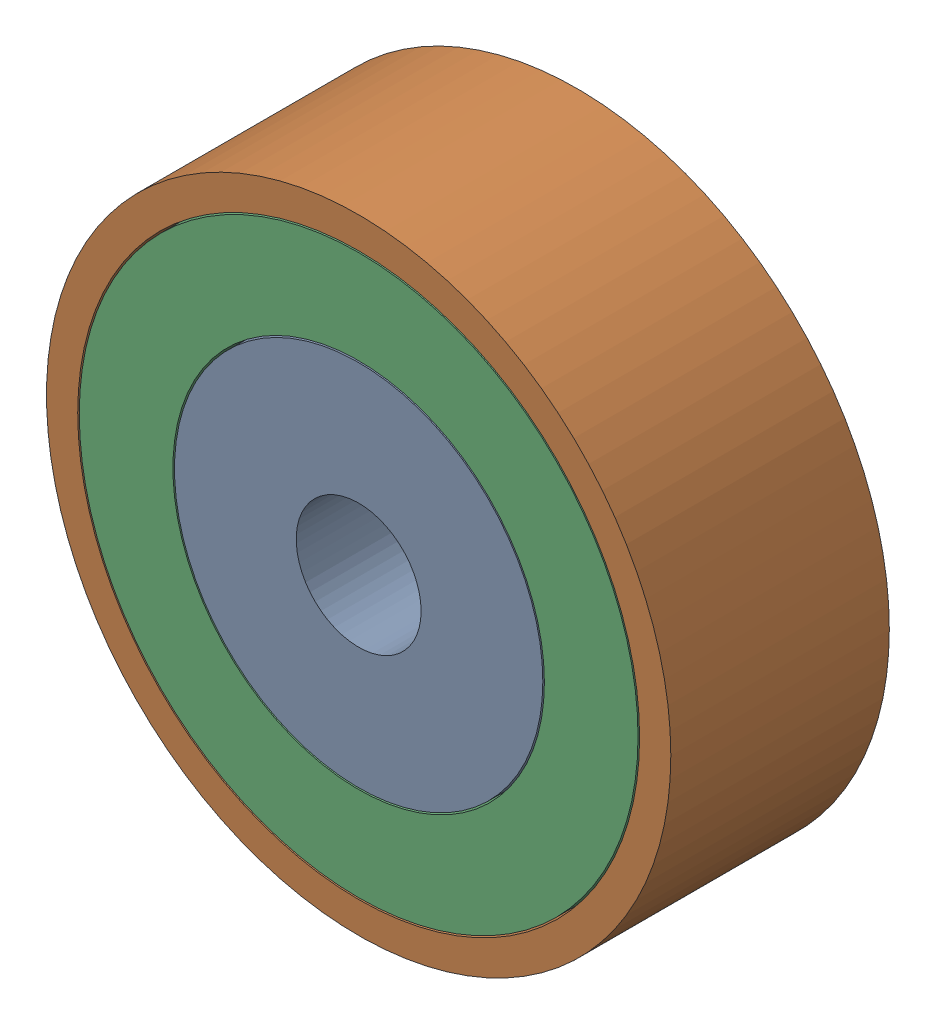
SolidWorks assembly 镜向轴承4, configuration 默认. Lengths in mm.
Overall size (20 20 7).
3 component instances, 3 part files, 4 mates.
Components (placement in the parent):
- 镜向轴承内圈-1: 镜向轴承内圈 [默认] at (-5.0655 0.8032 -6.5) size (11.8 11.8 7)
- 镜向轴承外圈-1: 镜向轴承外圈 [默认] at (-5.0655 0.8032 -6.5) size (20 20 7)
- 镜向轴承中圈-1: 镜向轴承中圈 [默认] at (-5.0655 0.8032 -6.5) size (17.9 17.9 7)
Mates (geometry in assembly coordinates):
- 重合1: coincident: plane of ? through (-5.0655 0.8032 -13.5) normal (0 0 -1); plane of ? through (-5.0655 0.8032 -13.5) normal (0 0 -1)
- 重合2: coincident: plane of ? through (-5.0655 0.8032 -13.5) normal (0 0 -1); plane of ? through (-5.0655 0.8032 -13.5) normal (0 0 -1)
- 同心1: concentric: cylinder of ? through (-5.0655 0.8032 -13.5) axis (0 0 1) radius 9; cylinder of ? through (-5.0655 0.8032 -13.5) axis (0 0 1) radius 8.95
- 同心2: concentric: cylinder of ? through (-5.0655 0.8032 -13.5) axis (0 0 1) radius 5.9; cylinder of ? through (-5.0655 0.8032 -13.5) axis (0 0 1) radius 5.95
